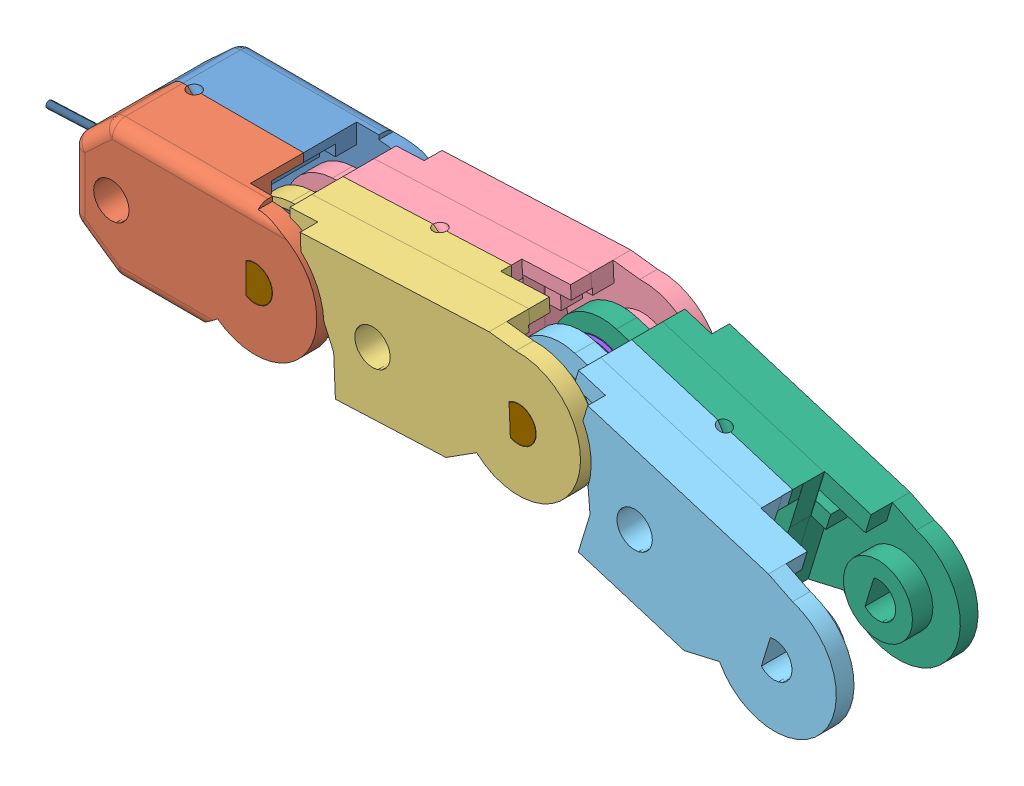
SolidWorks assembly Assem1, configuration Default. Lengths in mm.
Overall size (93.15 26.38 16.2).
11 component instances, 10 part files, 27 mates.
Components (placement in the parent):
- v2_digital_phalanx_left-1: v2_digital_phalanx_left [Default] at (9.8133 15.94 20.1262) size (27.7 15 8.04)
- v2_digital_phalanx_right-1: v2_digital_phalanx_right [Default] at (9.8133 15.94 20.1262) size (27.7 15 8.04)
- v2_medial_plalanx_left-1: v2_medial_plalanx_left [Default] at (9.8133 15.94 20.3262) x (0.999052 0.043533 0) z (0 0 1) size (42.66 14.5 8.01)
- v2_medial_plalanx_right-1: v2_medial_plalanx_right [Default] at (9.8133 15.94 20.3262) x (0.999052 0.043533 0) z (0 0 1) size (42.66 14.5 8.01)
- v2_proxiaml_plalanx_left-1: v2_proxiaml_plalanx_left [Default] at (39.7849 17.246 20.1262) x (0.956002 -0.293359 0) z (0 0 1) size (42.66 14.5 8.01)
- v2_proxiaml_plalanx_right-1: v2_proxiaml_plalanx_right [Default] at (39.7849 17.246 20.1262) x (0.956002 -0.293359 0) z (0 0 1) size (42.66 14.5 8.01)
- v2_pulley_dip-1: v2_pulley_dip [Default] at (9.8133 15.94 28.1262) size (8 8 2)
- v2_pulley_pip-1: v2_pulley_pip [Default] at (39.7849 17.246 27.6662) size (8 8 1.98)
- v2_shaft-1: v2_shaft [Default] at (39.7849 17.246 28.3262) x (0.999052 0.043533 0) z (0 0 1) size (3.9 3.9 16)
- v2_shaft-2: v2_shaft [Default] at (9.8133 15.94 28.1262) size (3.9 3.9 16)
- Sodemann_T030-180-250R.step-2: Sodemann_T030-180-250R.step [Standard] at (9.8133 15.94 30.6759) x (-0.043533 0.999052 0) z (0 0 1) size (10.49 50.8 8.02)
Mates (geometry in assembly coordinates):
- Coincident1: coincident anti-aligned: plane of v2_digital_phalanx_left-1 through (9.8133 15.94 28.1262) normal (0 0 1); plane of v2_digital_phalanx_right-1 through (9.8133 15.94 28.1262) normal (0 0 -1)
- Concentric1: concentric anti-aligned: cylinder of v2_digital_phalanx_left-1 through (9.8133 15.94 20.1262) axis (0 0 1) radius 2; cylinder of v2_digital_phalanx_right-1 through (9.8133 15.94 36.1262) axis (0 0 -1) radius 2
- Concentric2: concentric aligned: cylinder of v2_digital_phalanx_left-1 through (-6.3867 15.94 20.1262) axis (0 0 1) radius 0.95; cylinder of v2_digital_phalanx_right-1 through (-6.3867 15.94 20.1262) axis (0 0 1) radius 0.95
- Concentric3: concentric anti-aligned: cylinder of v2_medial_plalanx_left-1 through (23.3005 16.5277 36.3262) axis (0 0 -1) radius 0.95; cylinder of v2_medial_plalanx_right-1 through (23.3005 16.5277 20.3262) axis (0 0 1) radius 0.95
- Concentric4: concentric anti-aligned: cylinder of v2_medial_plalanx_left-1 through (9.8133 15.94 31.8262) axis (0 0 -1) radius 2.1; cylinder of v2_medial_plalanx_right-1 through (9.8133 15.94 24.8262) axis (0 0 1) radius 2.1
- Concentric5: concentric anti-aligned: cylinder of v2_medial_plalanx_left-1 through (39.7849 17.246 36.3262) axis (0 0 -1) radius 2; cylinder of v2_medial_plalanx_right-1 through (39.7849 17.246 20.3262) axis (0 0 1) radius 2
- Concentric6: concentric aligned: cylinder of v2_digital_phalanx_left-1 through (9.8133 15.94 20.1262) axis (0 0 1) radius 2; cylinder of v2_medial_plalanx_right-1 through (9.8133 15.94 24.8262) axis (0 0 1) radius 2.1
- Coincident2: coincident anti-aligned: plane of v2_digital_phalanx_right-1 through (9.8133 15.94 31.8262) normal (0 0 -1); plane of v2_medial_plalanx_left-1 through (9.8133 15.94 31.8262) normal (0 0 1)
- Coincident3: coincident anti-aligned: plane of v2_medial_plalanx_left-1 through (23.3005 16.5277 28.3262) normal (0 0 -1); plane of v2_medial_plalanx_right-1 through (23.3005 16.5277 28.3262) normal (0 0 1)
- Concentric7: concentric aligned: cylinder of v2_medial_plalanx_right-1 through (9.8133 15.94 24.8262) axis (0 0 1) radius 2.1; cylinder of v2_pulley_dip-1 through (9.8133 15.94 31.1408) axis (0 0 1) radius 2.1
- Coincident4: coincident anti-aligned: plane of v2_medial_plalanx_right-1 through (9.8133 15.94 27.1262) normal (0 0 1); plane of v2_pulley_dip-1 through (9.8133 19.94 27.1262) normal (0 0 -1)
- Concentric8: concentric anti-aligned: cylinder of v2_proxiaml_plalanx_left-1 through (52.6909 13.2856 36.1262) axis (0 0 -1) radius 0.95; cylinder of v2_proxiaml_plalanx_right-1 through (52.6909 13.2856 20.1262) axis (0 0 1) radius 0.95
- Concentric9: concentric anti-aligned: cylinder of v2_proxiaml_plalanx_left-1 through (39.7849 17.246 31.6262) axis (0 0 -1) radius 2.1; cylinder of v2_proxiaml_plalanx_right-1 through (39.7849 17.246 24.6262) axis (0 0 1) radius 2.1
- Coincident5: coincident anti-aligned: plane of v2_proxiaml_plalanx_left-1 through (52.6909 13.2856 28.1262) normal (0 0 -1); plane of v2_proxiaml_plalanx_right-1 through (52.6909 13.2856 28.1262) normal (0 0 1)
- Concentric10: concentric aligned: cylinder of v2_medial_plalanx_left-1 through (39.7849 17.246 36.3262) axis (0 0 -1) radius 2; cylinder of v2_proxiaml_plalanx_left-1 through (39.7849 17.246 31.6262) axis (0 0 -1) radius 2.1
- Coincident6: coincident anti-aligned: plane of v2_medial_plalanx_right-1 through (39.7849 17.246 24.6262) normal (0 0 1); plane of v2_proxiaml_plalanx_right-1 through (39.7849 17.246 24.6262) normal (0 0 -1)
- Concentric11: concentric aligned: cylinder of v2_digital_phalanx_right-1 through (9.8133 15.94 36.1262) axis (0 0 -1) radius 2; cylinder of v2_shaft-2 through (9.8133 15.94 36.1262) axis (0 0 -1) radius 1.95
- Coincident7: coincident anti-aligned: plane of v2_digital_phalanx_right-1 through (8.8133 17.6721 36.1262) normal (1 0 0); plane of v2_shaft-2 through (8.8133 17.6141 31.8262) normal (-1 0 0)
- Coincident8: coincident anti-aligned: plane of v2_digital_phalanx_right-1 through (9.8133 15.94 31.8262) normal (0 0 -1); plane of v2_shaft-2 through (9.8133 15.94 31.8262) normal (0 0 1)
- Concentric13: concentric aligned: cylinder of v2_medial_plalanx_left-1 through (39.7849 17.246 36.3262) axis (0 0 -1) radius 2; cylinder of v2_shaft-1 through (39.7849 17.246 36.3262) axis (0 0 -1) radius 1.95
- Coincident9: coincident anti-aligned: plane of v2_medial_plalanx_left-1 through (38.7104 18.9329 36.3262) normal (0.999052 0.043533 0); plane of v2_shaft-1 through (38.713 18.8749 32.0262) normal (-0.999052 -0.043533 0)
- Coincident10: coincident anti-aligned: plane of v2_medial_plalanx_left-1 through (39.7849 17.246 32.0262) normal (0 0 -1); plane of v2_shaft-1 through (39.7849 17.246 32.0262) normal (0 0 1)
- Concentric14: concentric anti-aligned: cylinder of v2_pulley_pip-1 through (39.7849 17.246 30.6808) axis (0 0 1) radius 2.1; cylinder of v2_shaft-1 through (39.7849 17.246 36.3262) axis (0 0 -1) radius 1.95
- Coincident11: coincident anti-aligned: plane of v2_proxiaml_plalanx_left-1 through (39.7849 17.246 29.3262) normal (0 0 -1); plane of v2_pulley_pip-1 through (39.7849 19.346 29.3262) normal (0 0 1)
- Concentric17: concentric aligned: cylinder of v2_digital_phalanx_right-1 through (9.8133 15.94 31.8262) axis (0 0 1) radius 3.9; circle of Sodemann_T030-180-250R.step-2
- Parallel4: parallel aligned: plane of v2_medial_plalanx_left-1 through (32.9967 19.1243 34.3262) normal (0.999052 0.043533 0); plane of Sodemann_T030-180-250R.step-2 through (34.9879 21.6663 30.6759) normal (0.999052 0.043533 0)
- Coincident18: coincident: plane of ? through (9.8133 15.94 34.1262) normal (0 0 -1); point of Sodemann_T030-180-250R.step-2
